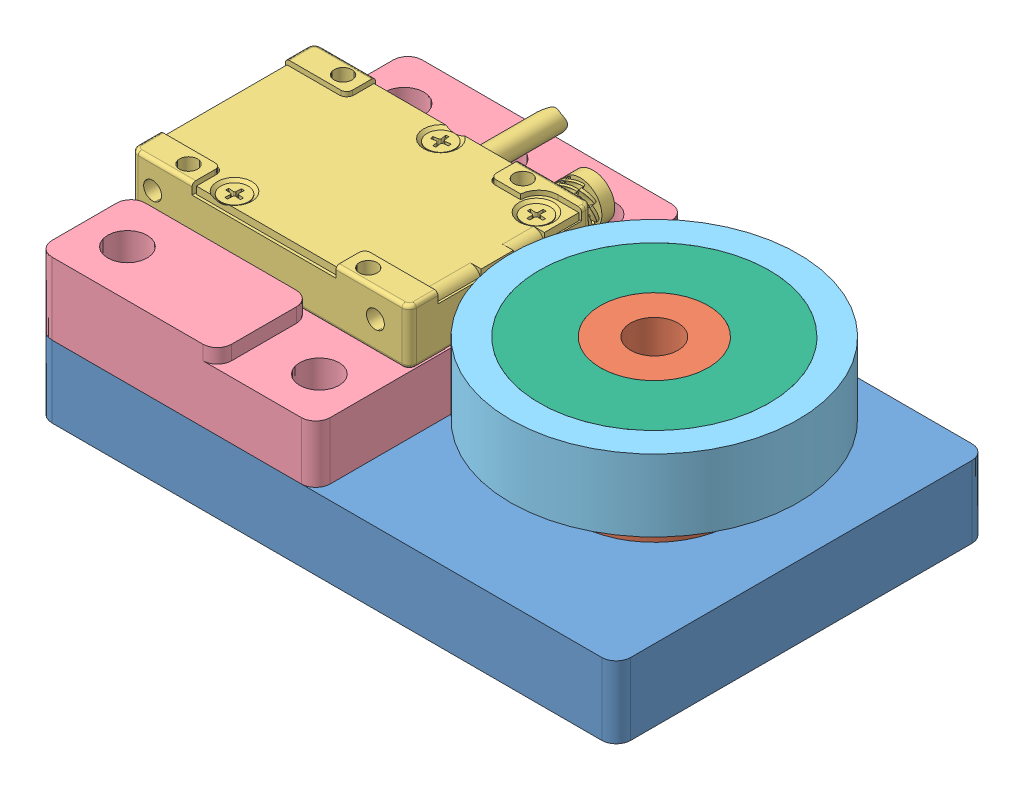
SolidWorks assembly jig, configuration Default. Lengths in mm.
Overall size (87.18 27.91 53.35).
6 component instances, 6 part files, 12 mates.
Components (placement in the parent):
- base-plate-1: base-plate [Default] at (28.1591 29.8677 67.6396) size (80.5 10 51.5)
- fixed-shaft-1: fixed-shaft [Default] at (48.4091 39.8677 68.0896) x (1 0 0) z (0 1 0) size (22 22 17)
- HR1-1: HR1 [Default] at (34.0702 51.7177 244.0285) x (1 0 0) z (0 1 0) size (41.28 36.18 10.9)
- motor-plate-1: motor-plate [Default] at (7.2591 39.8677 67.6396) size (38.7 10 51.5)
- ceramic-ring-1: ceramic-ring [Default] at (48.4091 56.8677 68.0896) x (-0.901945 0 0.431851) z (0 -1 0) size (40 40 10)
- rolling-element-bearing-1: rolling-element-bearing [Default] at (48.4091 56.8677 68.0896) x (0.75417 0 -0.65668) z (0 -1 0) size (32 32 9)
Mates (geometry in assembly coordinates):
- Coincident1: coincident anti-aligned: plane of base-plate-1 through (28.1591 39.8677 67.6396) normal (0 1 0); plane of motor-plate-1 through (7.2591 39.8677 67.6396) normal (0 -1 0)
- Concentric1: concentric aligned: cylinder of base-plate-1 through (-6.0909 29.8677 48.3896) axis (0 1 0) radius 2.5; cylinder of motor-plate-1 through (-6.0909 39.8677 48.3896) axis (0 1 0) radius 2.75
- Concentric2: concentric aligned: cylinder of base-plate-1 through (20.6091 29.8677 86.8896) axis (0 1 0) radius 2.5; cylinder of motor-plate-1 through (20.6091 39.8677 86.8896) axis (0 1 0) radius 2.75
- Coincident2: coincident anti-aligned: plane of base-plate-1 through (28.1591 39.8677 67.6396) normal (0 1 0); plane of fixed-shaft-1 through (48.4091 39.8677 68.0896) normal (0 -1 0)
- Concentric3: concentric aligned: cylinder of base-plate-1 through (48.4091 29.8677 68.0896) axis (0 1 0) radius 3; cylinder of fixed-shaft-1 through (48.4091 39.8677 68.0896) axis (0 1 0) radius 3.3
- Coincident3: coincident aligned: plane of HR1-1 through (25.6091 47.8677 79.3896) normal (0 1 0); plane of motor-plate-1 through (7.2591 47.8677 67.6396) normal (0 1 0)
- Coincident4: coincident aligned: plane of HR1-1 through (-11.0909 55.5677 80.3896) normal (0 0 -1); plane of motor-plate-1 through (12.9091 49.8677 80.3896) normal (0 0 -1)
- Concentric4: concentric anti-aligned: cylinder of HR1-1 through (18.9091 55.5677 78.3896) axis (0 -1 0) radius 1.25; cylinder of motor-plate-1 through (18.9091 39.8677 78.3896) axis (0 1 0) radius 1.5
- Concentric5: concentric anti-aligned: cylinder of ceramic-ring-1 through (48.4091 56.8677 68.0896) axis (0 -1 0) radius 16; cylinder of rolling-element-bearing-1 through (48.4091 47.8677 68.0896) axis (0 1 0) radius 16
- Concentric6: concentric aligned: cylinder of fixed-shaft-1 through (48.4091 56.8677 68.0896) axis (0 -1 0) radius 7.5; cylinder of rolling-element-bearing-1 through (48.4091 56.8677 68.0896) axis (0 -1 0) radius 7.5
- Coincident7: coincident anti-aligned: plane of fixed-shaft-1 through (48.4091 47.8677 68.0896) normal (0 1 0); plane of rolling-element-bearing-1 through (48.4091 47.8677 68.0896) normal (0 -1 0)
- Coincident9: coincident aligned: plane of ceramic-ring-1 through (48.4091 56.8677 68.0896) normal (0 1 0); plane of rolling-element-bearing-1 through (48.4091 56.8677 68.0896) normal (0 1 0)
